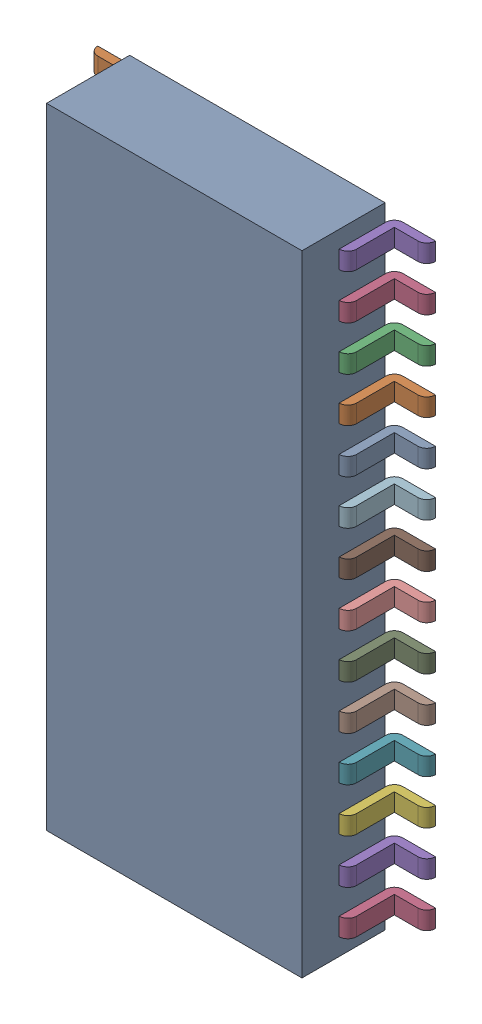
SolidWorks assembly U1, configuration Predeterminado. Lengths in mm.
Overall size (9.65 18 2.64).
30 component instances, 29 part files, 0 mates.
Components (placement in the parent):
- Open CASCADE STEP translator 6.8 1.3.1-1: Open CASCADE STEP translator 6.8 1.3.1 [Predeterminado] at origin size (9.65 18 2.64)
  - Body_1-1: Body_1 [Predeterminado] at origin size (7.3 18 2.38)
  - Pin_1-1: Pin_1 [Predeterminado] at origin size (1.17 0.51 1.58)
  - Pin_2-1: Pin_2 [Predeterminado] at origin size (1.17 0.51 1.58)
  - Pin_3-1: Pin_3 [Predeterminado] at origin size (1.17 0.51 1.58)
  - Pin_4-1: Pin_4 [Predeterminado] at origin size (1.17 0.51 1.58)
  - Pin_5-1: Pin_5 [Predeterminado] at origin size (1.17 0.51 1.58)
  - Pin_6-1: Pin_6 [Predeterminado] at origin size (1.17 0.51 1.58)
  - Pin_7-1: Pin_7 [Predeterminado] at origin size (1.17 0.51 1.58)
  - Pin_8-1: Pin_8 [Predeterminado] at origin size (1.17 0.51 1.58)
  - Pin_9-1: Pin_9 [Predeterminado] at origin size (1.17 0.51 1.58)
  - Pin_10-1: Pin_10 [Predeterminado] at origin size (1.17 0.51 1.58)
  - Pin_11-1: Pin_11 [Predeterminado] at origin size (1.17 0.51 1.58)
  - Pin_12-1: Pin_12 [Predeterminado] at origin size (1.17 0.51 1.58)
  - Pin_13-1: Pin_13 [Predeterminado] at origin size (1.17 0.51 1.58)
  - Pin_14-1: Pin_14 [Predeterminado] at origin size (1.17 0.51 1.58)
  - Pin_15-1: Pin_15 [Predeterminado] at (18.8 -17.78 0) x (-1 0 0) z (0 0 1) size (1.17 0.51 1.58)
  - Pin_16-1: Pin_16 [Predeterminado] at (18.8 -15.24 0) x (-1 0 0) z (0 0 1) size (1.17 0.51 1.58)
  - Pin_17-1: Pin_17 [Predeterminado] at (18.8 -12.7 0) x (-1 0 0) z (0 0 1) size (1.17 0.51 1.58)
  - Pin_18-1: Pin_18 [Predeterminado] at (18.8 -10.16 0) x (-1 0 0) z (0 0 1) size (1.17 0.51 1.58)
  - Pin_19-1: Pin_19 [Predeterminado] at (18.8 -7.62 0) x (-1 0 0) z (0 0 1) size (1.17 0.51 1.58)
  - Pin_20-1: Pin_20 [Predeterminado] at (18.8 -5.08 0) x (-1 0 0) z (0 0 1) size (1.17 0.51 1.58)
  - Pin_21-1: Pin_21 [Predeterminado] at (18.8 -2.54 0) x (-1 0 0) z (0 0 1) size (1.17 0.51 1.58)
  - Pin_22-1: Pin_22 [Predeterminado] at (18.8 0 0) x (-1 0 0) z (0 0 1) size (1.17 0.51 1.58)
  - Pin_23-1: Pin_23 [Predeterminado] at (18.8 2.54 0) x (-1 0 0) z (0 0 1) size (1.17 0.51 1.58)
  - Pin_24-1: Pin_24 [Predeterminado] at (18.8 5.08 0) x (-1 0 0) z (0 0 1) size (1.17 0.51 1.58)
  - Pin_25-1: Pin_25 [Predeterminado] at (18.8 7.62 0) x (-1 0 0) z (0 0 1) size (1.17 0.51 1.58)
  - Pin_26-1: Pin_26 [Predeterminado] at (18.8 10.16 0) x (-1 0 0) z (0 0 1) size (1.17 0.51 1.58)
  - Pin_27-1: Pin_27 [Predeterminado] at (18.8 12.7 0) x (-1 0 0) z (0 0 1) size (1.17 0.51 1.58)
  - Pin_28-1: Pin_28 [Predeterminado] at (18.8 15.24 0) x (-1 0 0) z (0 0 1) size (1.17 0.51 1.58)
